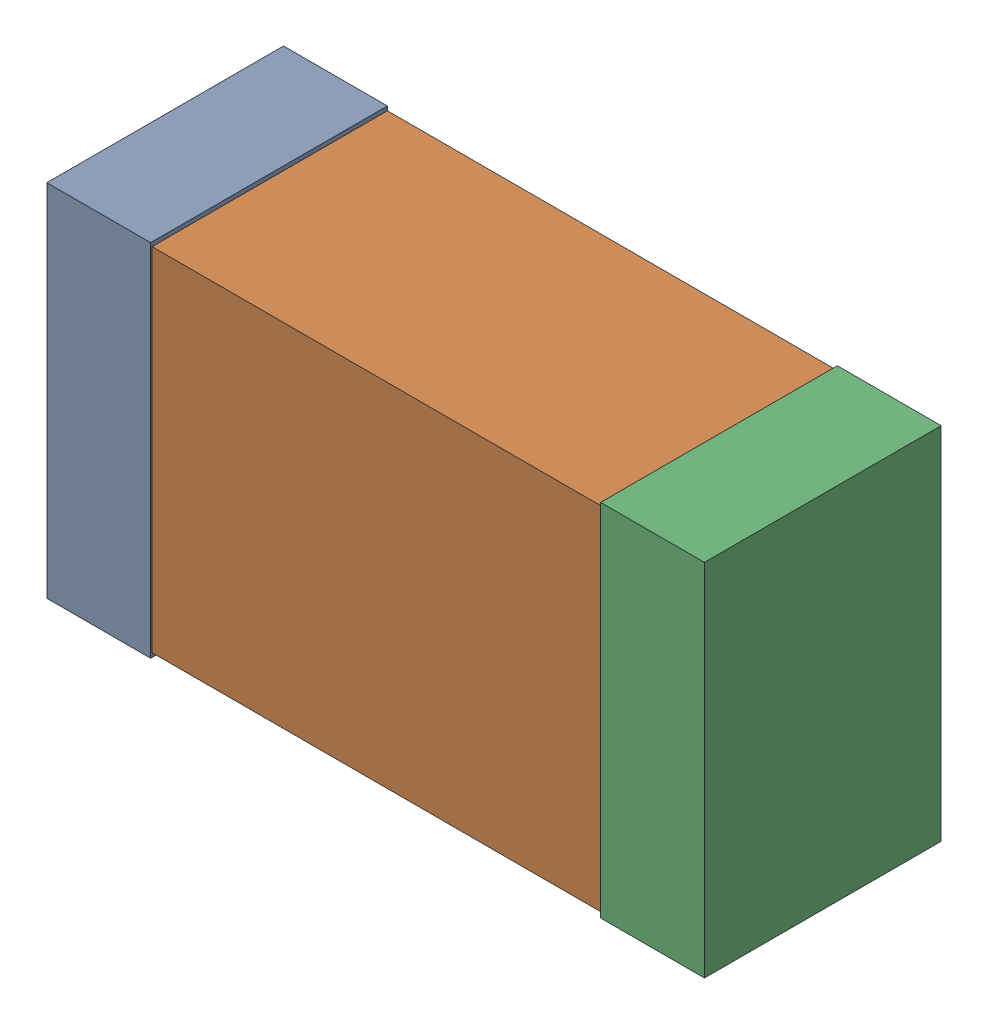
SolidWorks assembly R5Kanaloa_v2.0.0_Power, configuration Default. Lengths in mm.
Overall size (2.38 1.3 0.85).
6 component instances, 2 part files, 0 mates.
Components (placement in the parent):
- 352877648-1: 352877648 [Default] at (69.45 110.05 0) size (0.38 1.3 0.85)
  - Extruded_14-1: Extruded_14 [Default] at origin size (0.38 1.3 0.85)
- 352877904-1: 352877904 [Default] at (70.45 110.05 0) size (2.2 1.27 0.85)
  - Extruded_18-1: Extruded_18 [Default] at origin size (2.2 1.27 0.85)
- 352877648-2: 352877648 [Default] at (71.45 110.05 0) size (0.38 1.3 0.85)
  - Extruded_14-1: Extruded_14 [Default] at origin size (0.38 1.3 0.85)
